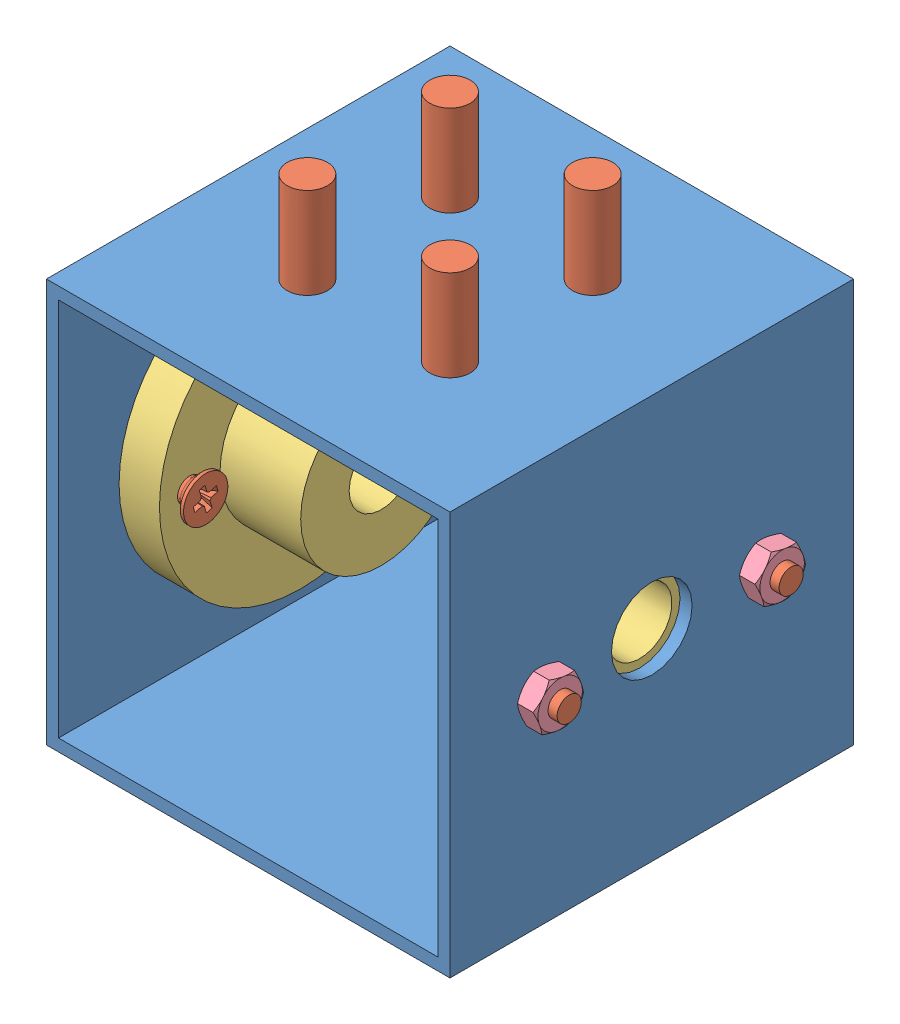
SolidWorks assembly Caixa Alumínio 2, configuration Valor predeterminado. Lengths in mm.
Overall size (57.04 61.26 50).
15 component instances, 4 part files, 22 mates.
Components (placement in the parent):
- Caixa Aluminio 1-1: Caixa Aluminio 1 [Valor predeterminado] at (-10.3148 1.616 25) size (50 50 50)
- countersunk flat head cross recess screw_iso-1: countersunk flat head cross recess screw_iso [ISO 7046-1 - M3 x 12 - Z - 12N] at (-26.8335 1.616 63.75) x (-1 0 0) z (0 -0.954727 -0.297484) size (12 5.5 5.5)
- countersunk flat head cross recess screw_iso-2: countersunk flat head cross recess screw_iso [ISO 7046-1 - M5 x 16 - Z - 16N] at (-1.476 21.8775 41.1612) x (0 1 0) z (0.529882 0 -0.848071) size (16 9.3 9.3)
- Bucha 8 mm-1: Bucha 8 mm [Valor predeterminado] at (-33.8148 1.616 50) x (0 -1 0) z (0 0 1) size (35 15 35)
- Bucha 8 mm-2: Bucha 8 mm [Valor predeterminado] at (13.1852 1.616 50) x (0 1 0) z (0 0 1) size (35 15 35)
- countersunk flat head cross recess screw_iso-3: countersunk flat head cross recess screw_iso [ISO 7046-1 - M3 x 12 - Z - 12N] at (6.2038 1.616 36.25) x (1 0 0) z (0 -0.08962 0.995976) size (12 5.5 5.5)
- countersunk flat head cross recess screw_iso-4: countersunk flat head cross recess screw_iso [ISO 7046-1 - M3 x 12 - Z - 12N] at (6.2038 1.616 63.75) x (1 0 0) z (0 -0.08962 0.995976) size (12 5.5 5.5)
- countersunk flat head cross recess screw_iso-5: countersunk flat head cross recess screw_iso [ISO 7046-1 - M3 x 12 - Z - 12N] at (-26.8335 1.616 36.25) x (-1 0 0) z (0 -0.954727 -0.297484) size (12 5.5 5.5)
- countersunk flat head cross recess screw_iso-6: countersunk flat head cross recess screw_iso [ISO 7046-1 - M5 x 16 - Z - 16N] at (-19.1537 21.8775 58.8388) x (0 1 0) z (0.529882 0 -0.848071) size (16 9.3 9.3)
- countersunk flat head cross recess screw_iso-7: countersunk flat head cross recess screw_iso [ISO 7046-1 - M5 x 16 - Z - 16N] at (-1.476 21.8775 58.8388) x (0 1 0) z (0.529882 0 -0.848071) size (16 9.3 9.3)
- countersunk flat head cross recess screw_iso-8: countersunk flat head cross recess screw_iso [ISO 7046-1 - M5 x 16 - Z - 16N] at (-19.1537 21.8775 41.1612) x (0 1 0) z (0.529882 0 -0.848071) size (16 9.3 9.3)
- hex nut style 1 gradeab_iso-1: hex nut style 1 gradeab_iso [ISO - 4032 - M3 - D - N] at (-35.3148 1.616 63.75) x (0 0.352257 0.935903) z (1 0 0) size (5.5 6.35 2.4)
- hex nut style 1 gradeab_iso-2: hex nut style 1 gradeab_iso [ISO - 4032 - M3 - D - N] at (-35.3148 1.616 36.25) x (0 0.352257 0.935903) z (1 0 0) size (5.5 6.35 2.4)
- hex nut style 1 gradeab_iso-3: hex nut style 1 gradeab_iso [ISO - 4032 - M3 - D - N] at (14.6852 1.616 63.75) x (0 -0.352257 0.935903) z (-1 0 0) size (5.5 6.35 2.4)
- hex nut style 1 gradeab_iso-4: hex nut style 1 gradeab_iso [ISO - 4032 - M3 - D - N] at (14.6852 1.616 36.25) x (0 -0.352257 0.935903) z (-1 0 0) size (5.5 6.35 2.4)
Mates (geometry in assembly coordinates):
- Coincident1: coincident: plane of Caixa Aluminio 1-1 through (-33.8148 -21.884 75) normal (1 0 0); plane of Bucha 8 mm-1 through (-33.8148 1.616 50) normal (-1 0 0)
- Concentric1: concentric: cylinder of Caixa Aluminio 1-1 through (-35.3148 1.616 50) axis (1 0 0) radius 5; cylinder of Bucha 8 mm-1 through (-33.8148 1.616 50) axis (1 0 0) radius 4
- Concentric2: concentric: cylinder of Caixa Aluminio 1-1 through (-35.3148 1.616 63.75) axis (1 0 0) radius 1.5; cylinder of Bucha 8 mm-1 through (-38.8148 1.616 63.75) axis (1 0 0) radius 1.5
- Coincident2: coincident: circle of countersunk flat head cross recess screw_iso-1; circle of Bucha 8 mm-1
- Coincident3: coincident: plane of Caixa Aluminio 1-1 through (13.1852 -21.884 75) normal (-1 0 0); plane of Bucha 8 mm-2 through (13.1852 1.616 50) normal (1 0 0)
- Concentric3: concentric: cylinder of Caixa Aluminio 1-1 through (-35.3148 1.616 50) axis (1 0 0) radius 5; cylinder of Bucha 8 mm-2 through (13.1852 1.616 50) axis (-1 0 0) radius 4
- Coincident4: coincident: cylinder of Caixa Aluminio 1-1 through (-35.3148 1.616 63.75) axis (1 0 0) radius 1.5; circle of Bucha 8 mm-2
- Coincident5: coincident: circle of countersunk flat head cross recess screw_iso-4; circle of Bucha 8 mm-2
- Coincident6: coincident: circle of Bucha 8 mm-2; circle of countersunk flat head cross recess screw_iso-3
- Coincident7: coincident: circle of Bucha 8 mm-1; circle of countersunk flat head cross recess screw_iso-5
- Coincident8: coincident: circle of Caixa Aluminio 1-1; circle of countersunk flat head cross recess screw_iso-2
- Coincident9: coincident: circle of Caixa Aluminio 1-1; circle of countersunk flat head cross recess screw_iso-6
- Coincident10: coincident: circle of Caixa Aluminio 1-1; circle of countersunk flat head cross recess screw_iso-8
- Coincident11: coincident: circle of Caixa Aluminio 1-1; circle of countersunk flat head cross recess screw_iso-7
- Coincident12: coincident: plane of Caixa Aluminio 1-1 through (14.6852 -23.384 75) normal (1 0 0); plane of hex nut style 1 gradeab_iso-4 through (14.6852 4.5879 37.3686) normal (-1 0 0)
- Concentric4: concentric: circle of countersunk flat head cross recess screw_iso-3; circle of hex nut style 1 gradeab_iso-4
- Coincident14: coincident: plane of Caixa Aluminio 1-1 through (14.6852 -23.384 75) normal (1 0 0); plane of hex nut style 1 gradeab_iso-3 through (14.6852 4.5879 64.8686) normal (-1 0 0)
- Concentric5: concentric: circle of countersunk flat head cross recess screw_iso-4; circle of hex nut style 1 gradeab_iso-3
- Coincident16: coincident: plane of Caixa Aluminio 1-1 through (-35.3148 -23.384 75) normal (-1 0 0); plane of hex nut style 1 gradeab_iso-1 through (-35.3148 -1.3559 64.8686) normal (1 0 0)
- Concentric6: concentric: circle of countersunk flat head cross recess screw_iso-1; circle of hex nut style 1 gradeab_iso-1
- Coincident21: coincident: plane of Caixa Aluminio 1-1 through (-35.3148 -23.384 75) normal (-1 0 0); plane of hex nut style 1 gradeab_iso-2 through (-35.3148 -1.3559 37.3686) normal (1 0 0)
- Concentric7: concentric: circle of countersunk flat head cross recess screw_iso-5; circle of hex nut style 1 gradeab_iso-2
